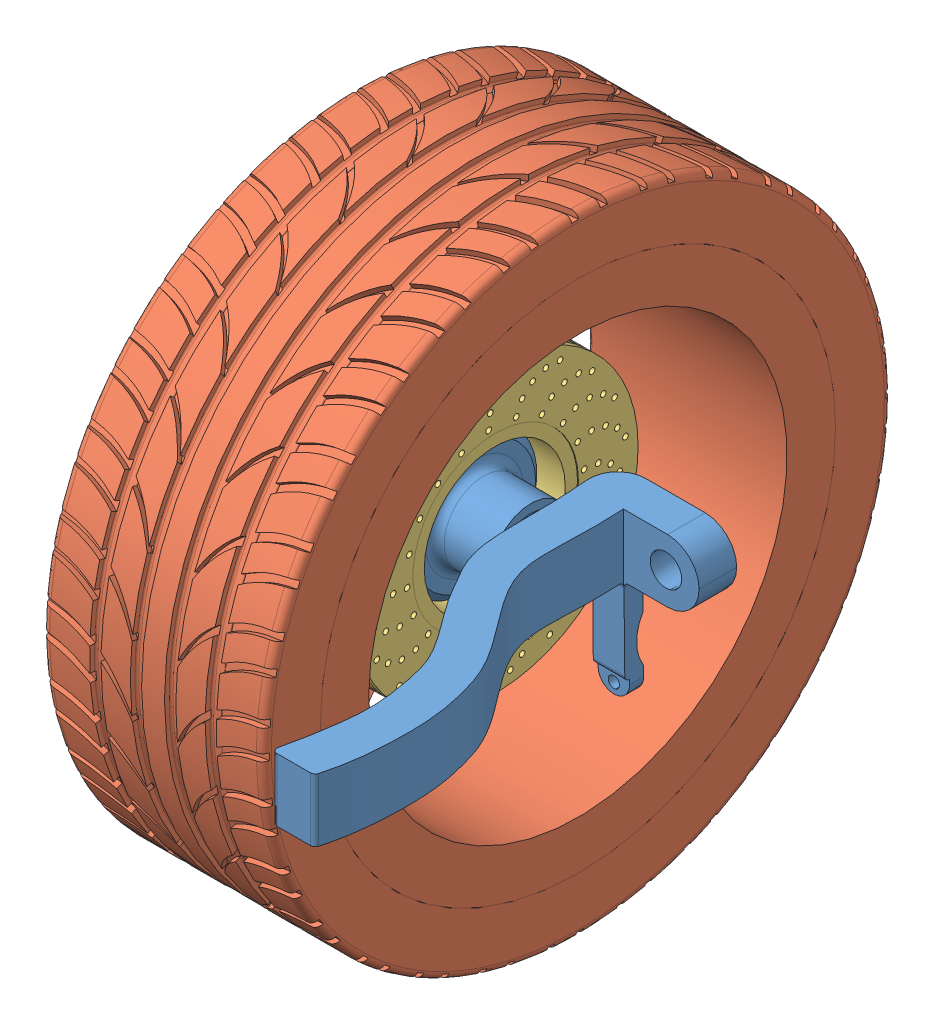
SolidWorks assembly Assem8, configuration Default. Lengths in mm.
Overall size (361.62 668.92 691.48).
3 component instances, 3 part files, 5 mates.
Components (placement in the parent):
- KHUNG TREO L-1: KHUNG TREO L [Default] x (-1 0 0) z (0 -1 0) size (231.48 449.46 221.1)
- BÁNH XE-1: BÁNH XE [Varsayılan] at (713.4994 0 0) x (0 1 0) z (0 0 1) size (668.92 273.92 668.92)
- ĐĨA THẮNG-1: ĐĨA THẮNG [Default] at (-96.4435 0 0) x (0 1 0) z (0 0 1) size (303 56.33 303)
Mates (geometry in assembly coordinates):
- Coincident4: coincident: point of KHUNG TREO L-1
- Concentric1: concentric anti-aligned: circle of BÁNH XE-1; circle of ĐĨA THẮNG-1
- Coincident5: coincident anti-aligned: plane of BÁNH XE-1 through (-284.0476 -22.5158 16.1489) normal (1 0 0); plane of ĐĨA THẮNG-1 through (-593.5295 -35 0) normal (-1 0 0)
- Concentric2: concentric aligned: circle of KHUNG TREO L-1; circle of ĐĨA THẮNG-1
- Coincident8: coincident anti-aligned: plane of KHUNG TREO L-1 through (-140.2735 0 0) normal (-1 0 0); plane of BÁNH XE-1 through (-140.2735 0 0) normal (1 0 0)
